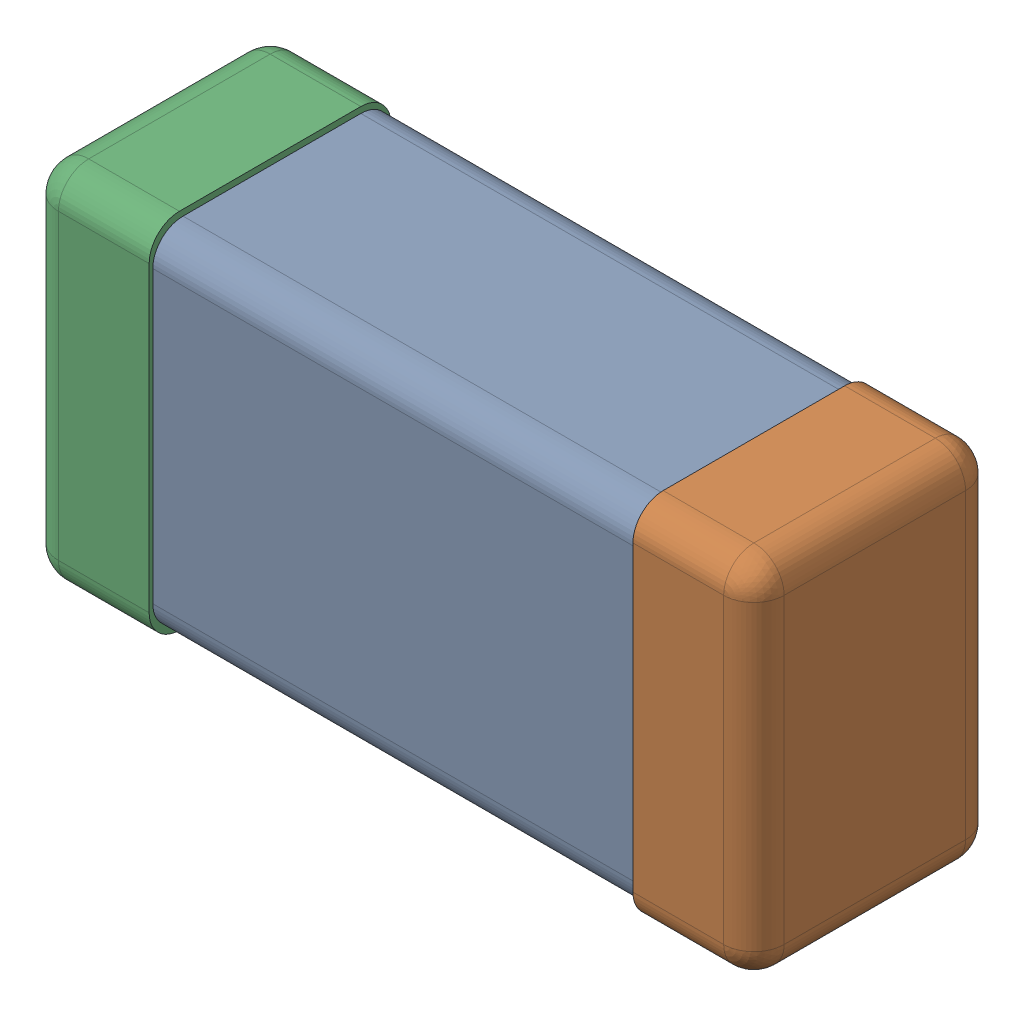
SolidWorks assembly C0201_020_11, configuration Standard. Lengths in mm.
Overall size (0.6 0.3 0.2).
3 component instances, 3 part files, 0 mates.
Components (placement in the parent):
- Part 3_2-1: Part 3_2 [Standard] at (0 0 -7.3015) size (0.5 0.29 0.2)
- Part 2_2-1: Part 2_2 [Standard] at (0 0 -7.3) size (0.1 0.3 0.2)
- Part 1_2-1: Part 1_2 [Standard] at (0 0 -7.3) size (0.1 0.3 0.2)
